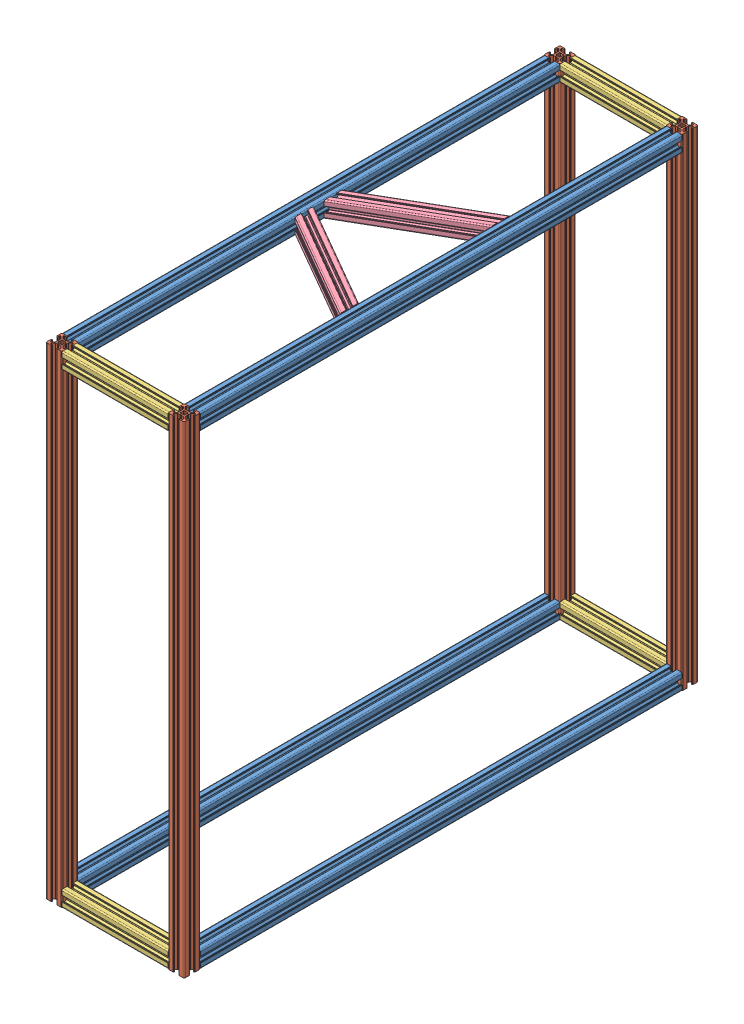
SolidWorks assembly frame, configuration Default. Lengths in mm.
Overall size (172.23 600 640).
14 component instances, 4 part files, 43 mates.
Components (placement in the parent):
- alu-frame-length-1: alu-frame-length [End Finishing_Non-Machined End Finish Options_Type_Single_] at origin size (20 20 600)
- alu-frame-height-1: alu-frame-height [End Finishing_Non-Machined End Finish Options_Type_Single_] at (0 -10 610) x (1 0 0) z (0 1 0) size (20 20 600)
- alu-frame-height-2: alu-frame-height [End Finishing_Non-Machined End Finish Options_Type_Single_] at (0 -10 -10) x (1 0 0) z (0 1 0) size (20 20 600)
- alu-frame-length-2: alu-frame-length [End Finishing_Non-Machined End Finish Options_Type_Single_] at (0 580 0) size (20 20 600)
- alu-frame-width-1: alu-frame-width [End Finishing_Non-Machined End Finish Options_Type_Single_] at (10 0 610) x (0 0 -1) z (1 0 0) size (20 20 132.23)
- alu-frame-width-2: alu-frame-width [End Finishing_Non-Machined End Finish Options_Type_Single_] at (10 0 -10) x (0 0 -1) z (1 0 0) size (20 20 132.23)
- alu-frame-width-3: alu-frame-width [End Finishing_Non-Machined End Finish Options_Type_Single_] at (10 580 -10) x (0 0 -1) z (1 0 0) size (20 20 132.23)
- alu-frame-width-4: alu-frame-width [End Finishing_Non-Machined End Finish Options_Type_Single_] at (10 580 610) x (0 0 -1) z (1 0 0) size (20 20 132.23)
- alu-frame-height-3: alu-frame-height [End Finishing_Non-Machined End Finish Options_Type_Single_] at (152.23 -10 610) x (1 0 0) z (0 1 0) size (20 20 600)
- alu-frame-height-4: alu-frame-height [End Finishing_Non-Machined End Finish Options_Type_Single_] at (152.23 -10 -10) x (1 0 0) z (0 1 0) size (20 20 600)
- alu-frame-length-3: alu-frame-length [End Finishing_Non-Machined End Finish Options_Type_Single_] at (152.23 0 0) size (20 20 600)
- alu-frame-length-4: alu-frame-length [End Finishing_Non-Machined End Finish Options_Type_Single_] at (152.23 580 0) size (20 20 600)
- alu-frame-cross-strut-1: alu-frame-cross-strut [End Finishing_Non-Machined End Finish Options_Type_Single_] at (-10.4902 580 293.863) x (-0.5 0 -0.866025) z (0.866025 0 -0.5) size (20 20 164.23)
- alu-frame-cross-strut-2: alu-frame-cross-strut [End Finishing_Non-Machined End Finish Options_Type_Single_] at (-10.4902 580 306.137) x (-0.5 0 0.866025) z (0.866025 0 0.5) size (20 20 164.23)
Mates (geometry in assembly coordinates):
- Coincident1: coincident: plane of alu-frame-length-1 through (-8.5 8.5 600) normal (0 0 1); plane of alu-frame-height-1 through (3.75 590 600) normal (0 0 -1)
- Coincident2: coincident: plane of alu-frame-length-1 through (3.75 -10 600) normal (0 -1 0); plane of alu-frame-height-1 through (-8.5 -10 601.5) normal (0 -1 0)
- Coincident3: coincident: plane of alu-frame-length-1 through (10 3.75 600) normal (1 0 0); plane of alu-frame-height-1 through (10 590 606.25) normal (1 0 0)
- Coincident4: coincident: plane of alu-frame-length-1 through (-8.5 8.5 0) normal (0 0 -1); plane of alu-frame-height-2 through (3.75 590 0) normal (0 0 1)
- Coincident5: coincident: plane of alu-frame-length-1 through (10 3.75 600) normal (1 0 0); plane of alu-frame-height-2 through (10 590 -6.25) normal (1 0 0)
- Coincident6: coincident: plane of alu-frame-length-1 through (3.75 -10 600) normal (0 -1 0); plane of alu-frame-height-2 through (-8.5 -10 -18.5) normal (0 -1 0)
- Coincident7: coincident: plane of alu-frame-height-1 through (-3.75 590 600) normal (0 0 -1); plane of alu-frame-length-2 through (-8.5 588.5 600) normal (0 0 1)
- Coincident8: coincident: plane of alu-frame-height-1 through (10 590 606.25) normal (1 0 0); plane of alu-frame-length-2 through (10 583.75 600) normal (1 0 0)
- Coincident9: coincident: plane of alu-frame-height-1 through (-8.5 590 601.5) normal (0 1 0); plane of alu-frame-length-2 through (-3.75 590 600) normal (0 1 0)
- Coincident10: coincident: plane of alu-frame-height-1 through (3.75 590 620) normal (0 0 1); plane of alu-frame-width-1 through (142.23 3.75 620) normal (0 0 1)
- Coincident11: coincident: plane of alu-frame-height-1 through (10 590 606.25) normal (1 0 0); plane of alu-frame-width-1 through (10 8.5 618.5) normal (-1 0 0)
- Coincident12: coincident: plane of alu-frame-height-1 through (-8.5 -10 601.5) normal (0 -1 0); plane of alu-frame-width-1 through (142.23 -10 613.75) normal (0 -1 0)
- Coincident13: coincident: plane of alu-frame-height-2 through (3.75 590 -20) normal (0 0 -1); plane of alu-frame-width-2 through (142.23 3.75 -20) normal (0 0 -1)
- Coincident14: coincident: plane of alu-frame-height-2 through (10 590 -13.75) normal (1 0 0); plane of alu-frame-width-2 through (10 8.5 -1.5) normal (-1 0 0)
- Coincident16: coincident: plane of alu-frame-height-2 through (-8.5 -10 -18.5) normal (0 -1 0); plane of alu-frame-width-2 through (142.23 -10 -13.75) normal (0 -1 0)
- Coincident17: coincident: plane of alu-frame-height-2 through (-8.5 590 -18.5) normal (0 1 0); plane of alu-frame-width-3 through (142.23 590 -13.75) normal (0 1 0)
- Coincident18: coincident: plane of alu-frame-height-2 through (3.75 590 -20) normal (0 0 -1); plane of alu-frame-width-3 through (142.23 583.75 -20) normal (0 0 -1)
- Coincident19: coincident: plane of alu-frame-height-2 through (10 590 -13.75) normal (1 0 0); plane of alu-frame-width-3 through (10 588.5 -1.5) normal (-1 0 0)
- Coincident20: coincident: plane of alu-frame-height-1 through (-8.5 590 601.5) normal (0 1 0); plane of alu-frame-width-4 through (142.23 590 606.25) normal (0 1 0)
- Coincident21: coincident: plane of alu-frame-height-1 through (3.75 590 620) normal (0 0 1); plane of alu-frame-width-4 through (142.23 583.75 620) normal (0 0 1)
- Coincident22: coincident: plane of alu-frame-height-1 through (10 590 613.75) normal (1 0 0); plane of alu-frame-width-4 through (10 588.5 618.5) normal (-1 0 0)
- Coincident23: coincident: plane of alu-frame-width-4 through (142.23 590 606.25) normal (0 1 0); plane of alu-frame-height-3 through (143.73 590 601.5) normal (0 1 0)
- Coincident24: coincident: plane of alu-frame-width-4 through (142.23 583.75 620) normal (0 0 1); plane of alu-frame-height-3 through (155.98 590 620) normal (0 0 1)
- Coincident25: coincident: plane of alu-frame-width-4 through (142.23 588.5 618.5) normal (1 0 0); plane of alu-frame-height-3 through (142.23 590 606.25) normal (-1 0 0)
- Coincident26: coincident: plane of alu-frame-width-3 through (142.23 590 -13.75) normal (0 1 0); plane of alu-frame-height-4 through (143.73 590 -18.5) normal (0 1 0)
- Coincident27: coincident: plane of alu-frame-width-3 through (142.23 583.75 0) normal (0 0 1); plane of alu-frame-height-4 through (155.98 590 0) normal (0 0 1)
- Coincident28: coincident: plane of alu-frame-width-3 through (142.23 588.5 -1.5) normal (1 0 0); plane of alu-frame-height-4 through (142.23 590 -13.75) normal (-1 0 0)
- Coincident29: coincident: plane of alu-frame-height-3 through (162.23 590 606.25) normal (1 0 0); plane of alu-frame-length-3 through (162.23 3.75 600) normal (1 0 0)
- Coincident30: coincident: plane of alu-frame-height-3 through (143.73 -10 601.5) normal (0 -1 0); plane of alu-frame-length-3 through (155.98 -10 600) normal (0 -1 0)
- Coincident31: coincident: plane of alu-frame-height-3 through (155.98 590 600) normal (0 0 -1); plane of alu-frame-length-3 through (143.73 8.5 600) normal (0 0 1)
- Coincident32: coincident: plane of alu-frame-height-3 through (143.73 590 601.5) normal (0 1 0); plane of alu-frame-length-4 through (155.98 590 600) normal (0 1 0)
- Coincident33: coincident: plane of alu-frame-height-3 through (162.23 590 606.25) normal (1 0 0); plane of alu-frame-length-4 through (162.23 583.75 600) normal (1 0 0)
- Coincident34: coincident: plane of alu-frame-height-3 through (155.98 590 600) normal (0 0 -1); plane of alu-frame-length-4 through (143.73 588.5 600) normal (0 0 1)
- Coincident35: coincident: plane of alu-frame-length-2 through (3.75 590 600) normal (0 1 0); plane of alu-frame-cross-strut-1 through (164.5899 590 197.1106) normal (0 1 0)
- Coincident36: coincident: plane of alu-frame-length-2 through (10 583.75 600) normal (1 0 0); plane of alu-frame-cross-strut-1 through (10 570 270.486) normal (-1 0 0)
- Distance1: distance = 6.42 mm: line of alu-frame-cross-strut-1 through (10 583.75 293.58) axis (0 1 0); plane of assembly
- Coincident38: coincident: plane of alu-frame-length-2 through (3.75 590 600) normal (0 1 0); plane of alu-frame-cross-strut-2 through (164.5899 590 402.8894) normal (0 1 0)
- Coincident39: coincident: plane of alu-frame-length-2 through (10 583.75 600) normal (1 0 0); plane of alu-frame-cross-strut-2 through (10 590 329.514) normal (-1 0 0)
- Distance2: distance = 6.42 mm: line of alu-frame-cross-strut-2 through (10 588.5 306.42) axis (0 -1 0); plane of assembly
- Coincident40: coincident: plane of alu-frame-height-1 through (-3.75 590 600) normal (0 0 -1); plane of ? through (-8.5 59.3633 600) normal (0 0 1)
- Coincident41: coincident: plane of alu-frame-height-1 through (10 590 606.25) normal (1 0 0); plane of ? through (10 54.6133 600) normal (1 0 0)
- Coincident42: coincident: plane of alu-frame-height-3 through (162.23 590 606.25) normal (1 0 0); plane of ? through (162.23 60.4604 600) normal (1 0 0)
- Coincident43: coincident: plane of alu-frame-height-3 through (148.48 590 600) normal (0 0 -1); plane of ? through (143.73 65.2104 600) normal (0 0 1)
